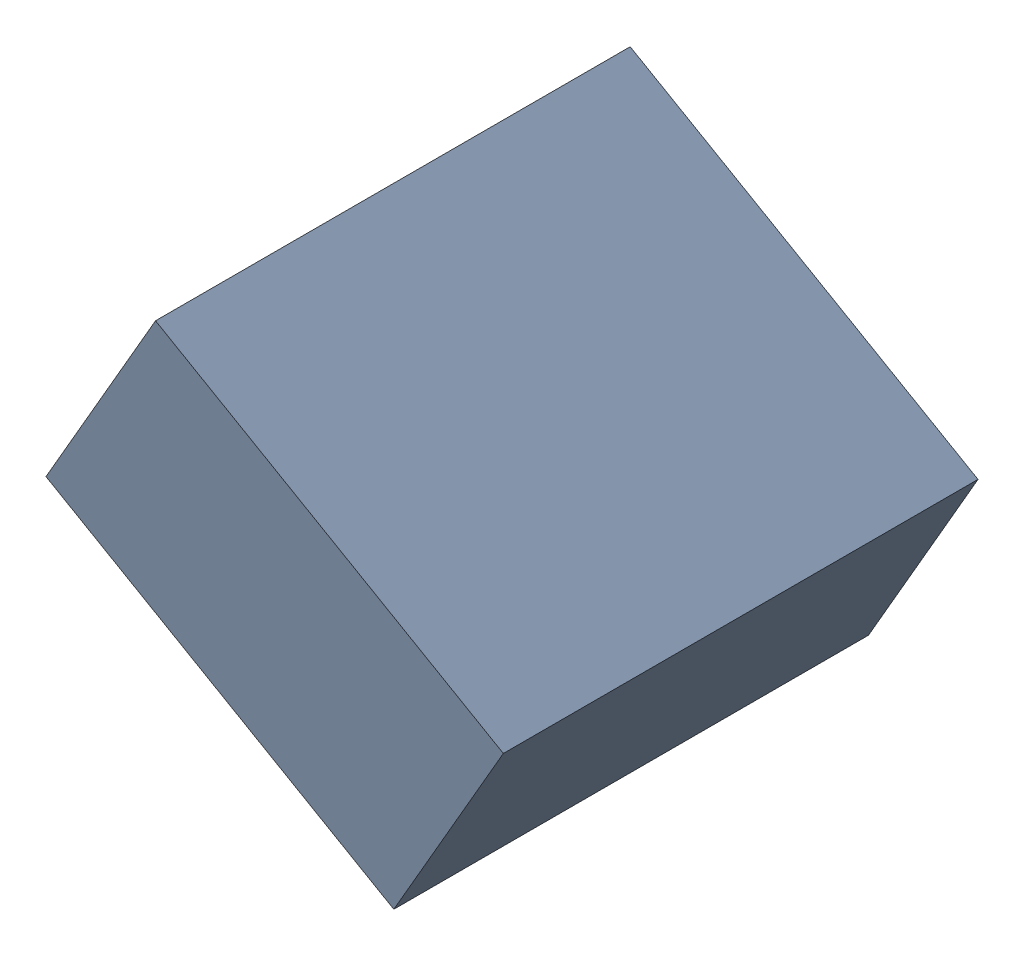
SolidWorks assembly C30_TDA3, configuration Standard. Lengths in mm.
Overall size (1.25 1.07 1.3).
2 component instances, 1 part files, 0 mates.
Components (placement in the parent):
- 885543056-1: 885543056 [Standard] at (47.3095 -35.1089 0) size (1.25 1.07 1.3)
  - Extruded_23-1: Extruded_23 [Standard] at origin size (1.25 1.07 1.3)
